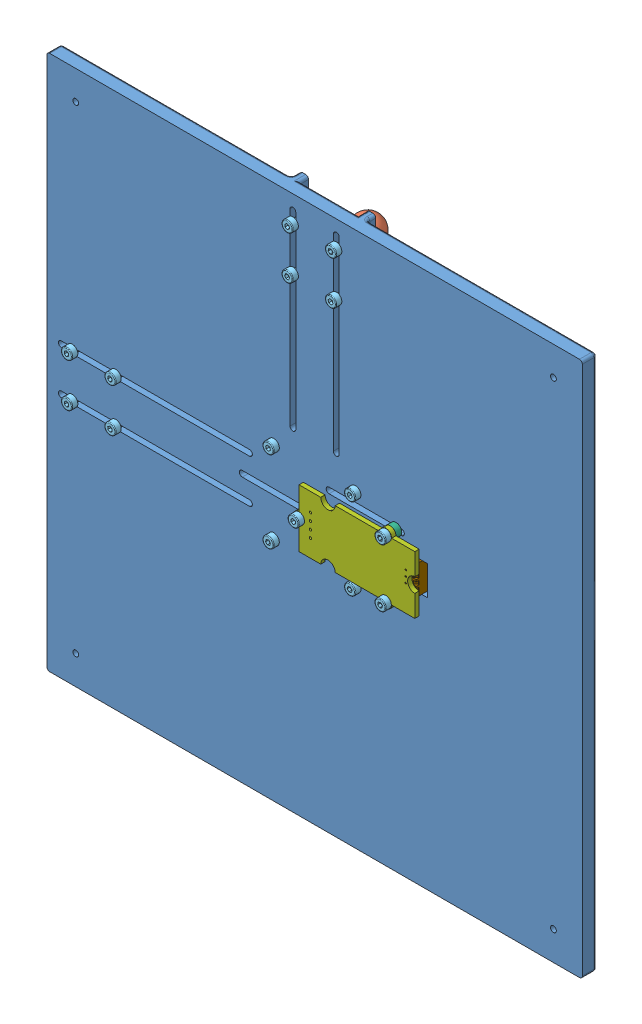
SolidWorks assembly plateau-complet, configuration Défaut. Lengths in mm.
Overall size (185 185 29.5).
45 component instances, 9 part files, 99 mates.
Components (placement in the parent):
- plateau-1: plateau [Défaut] at (22.8083 8.2939 197.5) size (185 185 8)
- support-sphere-ecrou_m2-4: support-sphere-ecrou_m2 [Défaut] at (-53.3917 8.2939 184.1699) x (0 -1 0) z (1 0 0) size (20 18.33 20)
- support-sphere-ecrou_m2-3: support-sphere-ecrou_m2 [Défaut] at (22.8083 84.4939 184.1699) x (1 0 0) z (0 1 0) size (20 18.33 20)
- support-fourchette-ecrou_m2-large-1: support-fourchette-ecrou_m2-large [Défaut] at (22.8083 8.2939 183.5) x (1 0 0) z (0 1 0) size (35 19 35)
- ecrou-h-6: ecrou-h [6007 HU M2] at (30.3083 91.9939 195.1) x (0.866025 -0.5 0) z (-0.5 -0.866025 0) size (4 1.6 4.62)
- ecrou-h-7: ecrou-h [6007 HU M2] at (15.3083 76.9939 195.1) x (-0.866025 -0.5 0) z (-0.5 0.866025 0) size (4 1.6 4.62)
- ecrou-h-8: ecrou-h [6007 HU M2] at (30.3083 76.9939 195.1) x (0.866025 0.5 0) z (0.5 -0.866025 0) size (4 1.6 4.62)
- ecrou-h-9: ecrou-h [6007 HU M2] at (15.3083 91.9939 195.1) x (0 -1 0) z (-1 0 0) size (4 1.6 4.62)
- ecrou-h-10: ecrou-h [6007 HU M2] at (-60.8917 15.7939 195.1) x (-0.5 -0.866025 0) z (-0.866025 0.5 0) size (4 1.6 4.62)
- ecrou-h-11: ecrou-h [6007 HU M2] at (-60.8917 0.7939 195.1) x (0.5 0.866025 0) z (0.866025 -0.5 0) size (4 1.6 4.62)
- ecrou-h-12: ecrou-h [6007 HU M2] at (-45.8917 0.7939 195.1) x (0.5 -0.866025 0) z (-0.866025 -0.5 0) size (4 1.6 4.62)
- ecrou-h-13: ecrou-h [6007 HU M2] at (-45.8917 15.7939 195.1) x (-0.5 -0.866025 0) z (-0.866025 0.5 0) size (4 1.6 4.62)
- vis-chc-15: vis-chc [Vis CHC M2x12] at (-45.8917 0.7939 202.5) x (0.832658 0.553787 0) z (0.553787 -0.832658 0) size (3.8 14 3.8)
- vis-chc-16: vis-chc [Vis CHC M2x12] at (-45.8917 15.7939 202.5) x (0.872712 0.488236 0) z (0.488236 -0.872712 0) size (3.8 14 3.8)
- vis-chc-17: vis-chc [Vis CHC M2x12] at (-60.8917 0.7939 202.5) x (0.878735 -0.477309 0) z (-0.477309 -0.878735 0) size (3.8 14 3.8)
- vis-chc-18: vis-chc [Vis CHC M2x12] at (-60.8917 15.7939 202.5) x (-0.020688 -0.999786 0) z (-0.999786 0.020688 0) size (3.8 14 3.8)
- vis-chc-19: vis-chc [Vis CHC M2x12] at (15.3083 76.9939 202.5) x (-0.459945 -0.887947 0) z (-0.887947 0.459945 0) size (3.8 14 3.8)
- vis-chc-20: vis-chc [Vis CHC M2x12] at (30.3083 76.9939 202.5) x (-0.307246 0.95163 0) z (0.95163 0.307246 0) size (3.8 14 3.8)
- vis-chc-21: vis-chc [Vis CHC M2x12] at (15.3083 91.9939 202.5) x (0.103271 -0.994653 0) z (-0.994653 -0.103271 0) size (3.8 14 3.8)
- vis-chc-22: vis-chc [Vis CHC M2x12] at (30.3083 91.9939 202.5) x (0.948564 0.316586 0) z (0.316586 -0.948564 0) size (3.8 14 3.8)
- vis-chc-23: vis-chc [Vis CHC M2x12] at (8.7083 22.3939 202.5) x (0.719096 0.694911 0) z (0.694911 -0.719096 0) size (3.8 14 3.8)
- vis-chc-24: vis-chc [Vis CHC M2x12] at (36.9083 22.3939 202.5) x (0.587191 0.809448 0) z (0.809448 -0.587191 0) size (3.8 14 3.8)
- vis-chc-25: vis-chc [Vis CHC M2x12] at (8.7083 -5.8061 202.5) x (0.239044 0.971009 0) z (0.971009 -0.239044 0) size (3.8 14 3.8)
- vis-chc-26: vis-chc [Vis CHC M2x12] at (36.9083 -5.8061 202.5) x (0.971464 0.237189 0) z (0.237189 -0.971464 0) size (3.8 14 3.8)
- ecrou-h-14: ecrou-h [6007 HU M2] at (8.7083 22.3939 195.16) x (0.866025 -0.5 0) z (-0.5 -0.866025 0) size (4 1.6 4.62)
- ecrou-h-15: ecrou-h [6007 HU M2] at (8.7083 -5.8061 195.16) x (0 -1 0) z (-1 0 0) size (4 1.6 4.62)
- ecrou-h-16: ecrou-h [6007 HU M2] at (36.9083 -5.8061 195.16) x (0.866025 -0.5 0) z (-0.5 -0.866025 0) size (4 1.6 4.62)
- ecrou-h-17: ecrou-h [6007 HU M2] at (36.9083 22.3939 195.16) x (0.866025 -0.5 0) z (-0.5 -0.866025 0) size (4 1.6 4.62)
- ecrou-h-18: ecrou-h [6007 HU M2] at (-59.6917 90.7939 200.5) x (0.866025 0.5 0) z (0.5 -0.866025 0) size (4 1.6 4.62)
- ecrou-h-19: ecrou-h [6007 HU M2] at (105.3083 90.7939 198.9) x (0.866025 0.5 0) z (-0.5 0.866025 0) size (4 1.6 4.62)
- ecrou-h-20: ecrou-h [6007 HU M2] at (-59.6917 -74.2061 200.5) x (0 -1 0) z (-1 0 0) size (4 1.6 4.62)
- ecrou-h-21: ecrou-h [6007 HU M2] at (105.3083 -74.2061 200.5) x (0 1 0) z (1 0 0) size (4 1.6 4.62)
- vis-chc-30: vis-chc [Vis CHC M2x8] at (50.9161 18.2939 206) x (-0.221467 -0.975168 0) z (-0.975168 0.221467 0) size (3.8 10 3.8)
- vis-chc-32: vis-chc [Vis CHC M2x8] at (50.9161 -1.7061 206) x (-0.923728 -0.383049 0) z (-0.383049 0.923728 0) size (3.8 10 3.8)
- vis-chc-33: vis-chc [Vis CHC M2x8] at (20.9161 8.2939 206) x (-0.787107 -0.616816 0) z (-0.616816 0.787107 0) size (3.8 10 3.8)
- ecrou-h-24: ecrou-h [6007 HU M2] at (20.9161 8.2939 197.9) x (0 -1 0) z (1 0 0) size (4 1.6 4.62)
- ecrou-h-25: ecrou-h [6007 HU M2] at (50.9161 -1.7061 197.9) x (0.866025 0.5 0) z (-0.5 0.866025 0) size (4 1.6 4.62)
- ecrou-h-26: ecrou-h [6007 HU M2] at (50.9161 18.2939 197.9) x (-0.866025 0.5 0) z (-0.5 -0.866025 0) size (4 1.6 4.62)
- entretoise-grove-1: entretoise-grove [Défaut] at (50.9161 18.2939 202.5) x (0.992185 0.124776 0) z (0 0 1) size (4 4 2)
- entretoise-grove-2: entretoise-grove [Défaut] at (20.9161 8.2939 202.5) x (0.16979 0.98548 0) z (0 0 1) size (4 4 2)
- entretoise-grove-3: entretoise-grove [Défaut] at (50.9161 -1.7061 202.5) x (0.064788 0.997899 0) z (0 0 1) size (4 4 2)
- Grove IMU - droit-1: Grove IMU - droit [Défaut] at (42.9373 5.8987 163.25) x (0 -1 0) z (0 0 1) size (24 42 9.5)
  - Grove IMU Board-1: Grove IMU Board [Défaut] at (-2.3952 -22.0212 41.25) size (24 42 1.5)
  - MPU9150-1: MPU9150 [Défaut] at (-3.0078 -7.8003 40.45) size (4 4 0.8)
  - Connecteur Grove - droit-1: Connecteur Grove - droit [Défaut] at (-2.3952 11.9788 41.25) x (-1 0 0) z (0 -1 0) size (10 11 5)
Mates (geometry in assembly coordinates):
- Coïncidente5: coincident anti-aligned: plane of plateau-1 through (22.8083 8.2939 197.5) normal (0 0 -1); plane of support-sphere-ecrou_m2-4 through (-53.3917 8.2939 197.5) normal (0 0 1)
- Coïncidente8: coincident anti-aligned: plane of plateau-1 through (22.8083 8.2939 197.5) normal (0 0 -1); plane of support-sphere-ecrou_m2-3 through (22.8083 84.4939 197.5) normal (0 0 1)
- Coïncidente12: coincident anti-aligned: plane of plateau-1 through (22.8083 8.2939 197.5) normal (0 0 -1); plane of support-fourchette-ecrou_m2-large-1 through (22.8083 8.2939 197.5) normal (0 0 1)
- Coaxiale9: concentric anti-aligned: cylinder of support-sphere-ecrou_m2-3 through (30.3083 91.9939 197.501) axis (0 0 -1) radius 1; cylinder of ecrou-h-m2-6 through (30.3083 91.9939 193.5) axis (0 0 1) radius 0.7835
- Coïncidente26: coincident anti-aligned: plane of support-sphere-ecrou_m2-3 through (22.8083 84.4939 195.1) normal (0 0 -1); plane of ecrou-h-m2-6 through (32.6177 91.9939 195.1) normal (0 0 1)
- Parallèle1: parallel anti-aligned: plane of support-sphere-ecrou_m2-3 through (27.9783 91.9939 195.1) normal (0.866025 -0.5 0); plane of ecrou-h-m2-6 through (29.1536 93.9939 193.5) normal (-0.866025 0.5 0)
- Coaxiale10: concentric anti-aligned: cylinder of support-sphere-ecrou_m2-3 through (15.3083 91.9939 197.501) axis (0 0 -1) radius 1; cylinder of ecrou-h-m2-9 through (15.3083 91.9939 193.5) axis (0 0 1) radius 0.7835
- Parallèle2: parallel anti-aligned: plane of support-sphere-ecrou_m2-3 through (14.1433 94.0118 195.1) normal (0 -1 0); plane of ecrou-h-m2-9 through (16.463 93.9939 193.5) normal (0 1 0)
- Coïncidente29: coincident anti-aligned: plane of support-sphere-ecrou_m2-3 through (22.8083 84.4939 195.1) normal (0 0 -1); plane of ecrou-h-m2-9 through (16.463 89.9939 195.1) normal (0 0 1)
- Coaxiale11: concentric anti-aligned: cylinder of support-sphere-ecrou_m2-3 through (15.3083 76.9939 197.501) axis (0 0 -1) radius 1; cylinder of ecrou-h-m2-7 through (15.3083 76.9939 193.5) axis (0 0 1) radius 0.7835
- Parallèle3: parallel anti-aligned: plane of support-sphere-ecrou_m2-3 through (12.9783 76.9939 195.1) normal (0.866025 -0.5 0); plane of ecrou-h-m2-7 through (14.1536 78.9939 193.5) normal (-0.866025 0.5 0)
- Coïncidente31: coincident anti-aligned: plane of support-sphere-ecrou_m2-3 through (22.8083 84.4939 195.1) normal (0 0 -1); plane of ecrou-h-m2-7 through (14.1536 74.9939 195.1) normal (0 0 1)
- Coaxiale12: concentric anti-aligned: cylinder of support-sphere-ecrou_m2-3 through (30.3083 76.9939 197.501) axis (0 0 -1) radius 1; cylinder of ecrou-h-m2-8 through (30.3083 76.9939 193.5) axis (0 0 1) radius 0.7835
- Parallèle4: parallel anti-aligned: plane of support-sphere-ecrou_m2-3 through (32.6383 76.9939 195.1) normal (-0.866025 0.5 0); plane of ecrou-h-m2-8 through (31.463 74.9939 193.5) normal (0.866025 -0.5 0)
- Coïncidente32: coincident anti-aligned: plane of support-sphere-ecrou_m2-3 through (22.8083 84.4939 195.1) normal (0 0 -1); plane of ecrou-h-m2-8 through (31.463 78.9939 195.1) normal (0 0 1)
- Coaxiale13: concentric anti-aligned: cylinder of support-sphere-ecrou_m2-4 through (-60.8917 15.7939 197.501) axis (0 0 -1) radius 1; cylinder of ecrou-h-m2-10 through (-60.8917 15.7939 193.5) axis (0 0 1) radius 0.7835
- Coaxiale14: concentric anti-aligned: cylinder of support-sphere-ecrou_m2-4 through (-60.8917 0.7939 197.501) axis (0 0 -1) radius 1; cylinder of ecrou-h-m2-11 through (-60.8917 0.7939 193.5) axis (0 0 1) radius 0.7835
- Coaxiale15: concentric anti-aligned: cylinder of support-sphere-ecrou_m2-4 through (-45.8917 0.7939 197.501) axis (0 0 -1) radius 1; cylinder of ecrou-h-m2-12 through (-45.8917 0.7939 193.5) axis (0 0 1) radius 0.7835
- Coaxiale16: concentric anti-aligned: cylinder of support-sphere-ecrou_m2-4 through (-45.8917 15.7939 197.501) axis (0 0 -1) radius 1; cylinder of ecrou-h-m2-13 through (-45.8917 15.7939 193.5) axis (0 0 1) radius 0.7835
- Parallèle5: parallel anti-aligned: plane of support-sphere-ecrou_m2-4 through (-43.8738 16.9589 195.1) normal (-1 0 0); plane of ecrou-h-m2-13 through (-43.8917 14.6392 193.5) normal (1 0 0)
- Parallèle6: parallel anti-aligned: plane of support-sphere-ecrou_m2-4 through (-58.8738 16.9589 195.1) normal (-1 0 0); plane of ecrou-h-m2-10 through (-58.8917 14.6392 193.5) normal (1 0 0)
- Parallèle7: parallel anti-aligned: plane of support-sphere-ecrou_m2-4 through (-58.8738 -0.3711 195.1) normal (-0.5 0.866025 0); plane of ecrou-h-m2-11 through (-60.8917 -1.5155 193.5) normal (0.5 -0.866025 0)
- Parallèle8: parallel anti-aligned: plane of support-sphere-ecrou_m2-4 through (-43.8738 -0.3711 195.1) normal (-0.5 0.866025 0); plane of ecrou-h-m2-12 through (-45.8917 -1.5155 193.5) normal (0.5 -0.866025 0)
- Coïncidente37: coincident anti-aligned: plane of support-sphere-ecrou_m2-4 through (-53.3917 8.2939 195.1) normal (0 0 -1); plane of ecrou-h-m2-10 through (-60.8917 13.4845 195.1) normal (0 0 1)
- Coïncidente38: coincident anti-aligned: plane of support-sphere-ecrou_m2-4 through (-53.3917 8.2939 195.1) normal (0 0 -1); plane of ecrou-h-m2-13 through (-45.8917 13.4845 195.1) normal (0 0 1)
- Coïncidente39: coincident anti-aligned: plane of support-sphere-ecrou_m2-4 through (-53.3917 8.2939 195.1) normal (0 0 -1); plane of ecrou-h-m2-11 through (-60.8917 3.1033 195.1) normal (0 0 1)
- Coïncidente40: coincident anti-aligned: plane of support-sphere-ecrou_m2-4 through (-53.3917 8.2939 195.1) normal (0 0 -1); plane of ecrou-h-m2-12 through (-43.8917 -0.3608 195.1) normal (0 0 1)
- Coaxiale17: concentric anti-aligned: cylinder of support-sphere-ecrou_m2-3 through (30.3083 91.9939 197.501) axis (0 0 -1) radius 1; cylinder of vis-chc-m2x10-8 through (30.3083 91.9939 190.5) axis (0 0 1) radius 1
- Coaxiale18: concentric anti-aligned: cylinder of support-sphere-ecrou_m2-3 through (15.3083 91.9939 197.501) axis (0 0 -1) radius 1; cylinder of vis-chc-m2x10-9 through (15.3083 91.9939 190.5) axis (0 0 1) radius 1
- Coaxiale19: concentric anti-aligned: cylinder of support-sphere-ecrou_m2-3 through (30.3083 76.9939 197.501) axis (0 0 -1) radius 1; cylinder of vis-chc-m2x10-11 through (30.3083 76.9939 190.5) axis (0 0 1) radius 1
- Coaxiale20: concentric anti-aligned: cylinder of support-sphere-ecrou_m2-3 through (15.3083 76.9939 197.501) axis (0 0 -1) radius 1; cylinder of vis-chc-m2x10-10 through (15.3083 76.9939 190.5) axis (0 0 1) radius 1
- Coaxiale21: concentric anti-aligned: cylinder of support-sphere-ecrou_m2-4 through (-45.8917 0.7939 197.501) axis (0 0 -1) radius 1; cylinder of vis-chc-m2-15 through (-45.8917 0.7939 190.5) axis (0 0 1) radius 1
- Coaxiale22: concentric anti-aligned: cylinder of support-sphere-ecrou_m2-4 through (-60.8917 0.7939 197.501) axis (0 0 -1) radius 1; cylinder of vis-chc-m2-17 through (-60.8917 0.7939 190.5) axis (0 0 1) radius 1
- Coaxiale23: concentric anti-aligned: cylinder of support-sphere-ecrou_m2-4 through (-60.8917 15.7939 197.501) axis (0 0 -1) radius 1; cylinder of vis-chc-m2-18 through (-60.8917 15.7939 190.5) axis (0 0 1) radius 1
- Coaxiale24: concentric anti-aligned: cylinder of support-sphere-ecrou_m2-4 through (-45.8917 15.7939 197.501) axis (0 0 -1) radius 1; cylinder of vis-chc-m2-16 through (-45.8917 15.7939 190.5) axis (0 0 1) radius 1
- Coïncidente41: coincident anti-aligned: plane of plateau-1 through (22.8083 8.2939 202.5) normal (0 0 1); plane of vis-chc-m2x10-10 through (15.3083 76.9939 202.5) normal (0 0 -1)
- Coïncidente42: coincident anti-aligned: plane of plateau-1 through (22.8083 8.2939 202.5) normal (0 0 1); plane of vis-chc-m2x10-9 through (15.3083 91.9939 202.5) normal (0 0 -1)
- Coïncidente43: coincident anti-aligned: plane of plateau-1 through (22.8083 8.2939 202.5) normal (0 0 1); plane of vis-chc-m2x10-8 through (30.3083 91.9939 202.5) normal (0 0 -1)
- Coïncidente44: coincident anti-aligned: plane of plateau-1 through (22.8083 8.2939 202.5) normal (0 0 1); plane of vis-chc-m2x10-11 through (30.3083 76.9939 202.5) normal (0 0 -1)
- Coïncidente45: coincident anti-aligned: plane of plateau-1 through (22.8083 8.2939 202.5) normal (0 0 1); plane of vis-chc-m2-17 through (-60.8917 0.7939 202.5) normal (0 0 -1)
- Coïncidente46: coincident anti-aligned: plane of plateau-1 through (22.8083 8.2939 202.5) normal (0 0 1); plane of vis-chc-m2-15 through (-45.8917 0.7939 202.5) normal (0 0 -1)
- Coïncidente47: coincident anti-aligned: plane of plateau-1 through (22.8083 8.2939 202.5) normal (0 0 1); plane of vis-chc-m2-16 through (-45.8917 15.7939 202.5) normal (0 0 -1)
- Coïncidente48: coincident anti-aligned: plane of plateau-1 through (22.8083 8.2939 202.5) normal (0 0 1); plane of vis-chc-m2-18 through (-60.8917 15.7939 202.5) normal (0 0 -1)
- Distance6: distance = 13.8 mm: cylinder of support-sphere-ecrou_m2-4 through (-53.3917 8.2939 193.5) axis (0 0 1) radius 2.5; plane of plateau-1 through (-69.6917 100.7939 202.5) normal (-1 0 0)
- Distance7: distance = 13.8 mm: cylinder of support-sphere-ecrou_m2-3 through (22.8083 84.4939 193.5) axis (0 0 1) radius 2.5; plane of plateau-1 through (-69.6917 100.7939 202.5) normal (0 1 0)
- Coaxiale25: concentric anti-aligned: cylinder of support-fourchette-ecrou_m2-large-1 through (36.9083 22.3939 197.501) axis (0 0 -1) radius 1; cylinder of ecrou-h-m2-17 through (36.9083 22.3939 193.56) axis (0 0 1) radius 0.7835
- Parallèle9: parallel anti-aligned: plane of support-fourchette-ecrou_m2-large-1 through (35.7433 24.4118 195.16) normal (0 -1 0); plane of ecrou-h-m2-17 through (38.063 24.3939 193.56) normal (0 1 0)
- Coïncidente50: coincident anti-aligned: plane of support-fourchette-ecrou_m2-large-1 through (22.8083 8.2939 195.16) normal (0 0 -1); plane of ecrou-h-m2-17 through (39.2177 22.3939 195.16) normal (0 0 1)
- Coaxiale26: concentric anti-aligned: cylinder of support-fourchette-ecrou_m2-large-1 through (36.9083 -5.8061 197.501) axis (0 0 -1) radius 1; cylinder of ecrou-h-m2-16 through (36.9083 -5.8061 193.56) axis (0 0 1) radius 0.7835
- Coïncidente51: coincident anti-aligned: plane of support-fourchette-ecrou_m2-large-1 through (22.8083 8.2939 195.16) normal (0 0 -1); plane of ecrou-h-m2-16 through (39.2177 -5.8061 195.16) normal (0 0 1)
- Parallèle10: parallel anti-aligned: plane of support-fourchette-ecrou_m2-large-1 through (35.7433 -3.7882 195.16) normal (0 -1 0); plane of ecrou-h-m2-16 through (38.063 -3.8061 193.56) normal (0 1 0)
- Coaxiale27: concentric anti-aligned: cylinder of support-fourchette-ecrou_m2-large-1 through (8.7083 -5.8061 197.501) axis (0 0 -1) radius 1; cylinder of ecrou-h-m2-15 through (8.7083 -5.8061 193.56) axis (0 0 1) radius 0.7835
- Parallèle11: parallel anti-aligned: plane of support-fourchette-ecrou_m2-large-1 through (9.8733 -7.8239 195.16) normal (0 1 0); plane of ecrou-h-m2-15 through (7.5536 -7.8061 193.56) normal (0 -1 0)
- Coïncidente54: coincident anti-aligned: plane of support-fourchette-ecrou_m2-large-1 through (22.8083 8.2939 195.16) normal (0 0 -1); plane of ecrou-h-m2-15 through (9.863 -7.8061 195.16) normal (0 0 1)
- Coaxiale28: concentric anti-aligned: cylinder of support-fourchette-ecrou_m2-large-1 through (8.7083 22.3939 197.501) axis (0 0 -1) radius 1; cylinder of ecrou-h-m2-14 through (8.7083 22.3939 193.56) axis (0 0 1) radius 0.7835
- Parallèle12: parallel anti-aligned: plane of support-fourchette-ecrou_m2-large-1 through (7.5433 24.4118 195.16) normal (0 -1 0); plane of ecrou-h-m2-14 through (9.863 24.3939 193.56) normal (0 1 0)
- Coïncidente56: coincident anti-aligned: plane of support-fourchette-ecrou_m2-large-1 through (22.8083 8.2939 195.16) normal (0 0 -1); plane of ecrou-h-m2-14 through (11.0177 22.3939 195.16) normal (0 0 1)
- Coaxiale29: concentric anti-aligned: cylinder of plateau-1 through (8.7083 -5.8061 202.501) axis (0 0 -1) radius 1; cylinder of vis-chc-m2-25 through (8.7083 -5.8061 190.5) axis (0 0 1) radius 1
- Coïncidente57: coincident anti-aligned: plane of plateau-1 through (22.8083 8.2939 202.5) normal (0 0 1); plane of vis-chc-m2-25 through (8.7083 -5.8061 202.5) normal (0 0 -1)
- Coaxiale30: concentric anti-aligned: cylinder of plateau-1 through (36.9083 -5.8061 202.501) axis (0 0 -1) radius 1; cylinder of vis-chc-26 through (36.9083 -5.8061 190.5) axis (0 0 1) radius 1
- Coïncidente58: coincident anti-aligned: plane of plateau-1 through (22.8083 8.2939 202.5) normal (0 0 1); plane of vis-chc-26 through (36.9083 -5.8061 202.5) normal (0 0 -1)
- Coaxiale31: concentric anti-aligned: cylinder of plateau-1 through (8.7083 22.3939 202.501) axis (0 0 -1) radius 1; cylinder of vis-chc-m2-23 through (8.7083 22.3939 190.5) axis (0 0 1) radius 1
- Coïncidente59: coincident anti-aligned: plane of plateau-1 through (22.8083 8.2939 202.5) normal (0 0 1); plane of vis-chc-m2-23 through (8.7083 22.3939 202.5) normal (0 0 -1)
- Coaxiale32: concentric anti-aligned: cylinder of plateau-1 through (36.9083 22.3939 202.501) axis (0 0 -1) radius 1; cylinder of vis-chc-m2-24 through (36.9083 22.3939 190.5) axis (0 0 1) radius 1
- Coïncidente60: coincident anti-aligned: plane of plateau-1 through (22.8083 8.2939 202.5) normal (0 0 1); plane of vis-chc-m2-24 through (36.9083 22.3939 202.5) normal (0 0 -1)
- Coaxiale33: concentric anti-aligned: circle of plateau-1; circle of ecrou-h-m2-19
- Coaxiale34: concentric anti-aligned: cylinder of plateau-1 through (-59.6917 90.7939 202.501) axis (0 0 -1) radius 1; cylinder of ecrou-h-18 through (-59.6917 90.7939 198.9) axis (0 0 1) radius 0.7835
- Coaxiale35: concentric anti-aligned: cylinder of plateau-1 through (-59.6917 -74.2061 202.501) axis (0 0 -1) radius 1; cylinder of ecrou-h-20 through (-59.6917 -74.2061 198.9) axis (0 0 1) radius 0.7835
- Coaxiale36: concentric anti-aligned: cylinder of plateau-1 through (105.3083 -74.2061 202.501) axis (0 0 -1) radius 1; cylinder of ecrou-h-21 through (105.3083 -74.2061 198.9) axis (0 0 1) radius 0.7835
- Coaxiale37: concentric aligned: cylinder of ecrou-h-m2-16 through (36.9083 -5.8061 193.56) axis (0 0 1) radius 0.7835; cylinder of vis-chc-26 through (36.9083 -5.8061 190.5) axis (0 0 1) radius 1
- Coaxiale38: concentric aligned: cylinder of ecrou-h-m2-14 through (8.7083 22.3939 193.56) axis (0 0 1) radius 0.7835; cylinder of vis-chc-m2-23 through (8.7083 22.3939 190.5) axis (0 0 1) radius 1
- Parallèle13: parallel aligned: plane of plateau-1 through (-69.6917 100.7939 202.5) normal (0 1 0); plane of support-sphere-ecrou_m2-3 through (12.8083 94.4939 197.5) normal (0 1 0)
- Distance8: distance = 0.1 mm anti-aligned: plane of support-sphere-ecrou_m2-3 through (12.8083 94.4939 197.5) normal (-1 0 0); plane of plateau-1 through (12.7083 30.7939 194.5) normal (1 0 0)
- Parallèle14: parallel aligned: plane of plateau-1 through (-69.6917 100.7939 202.5) normal (-1 0 0); plane of support-sphere-ecrou_m2-4 through (-63.3917 18.2939 197.5) normal (-1 0 0)
- Distance9: distance = 0.1 mm anti-aligned: plane of support-sphere-ecrou_m2-4 through (-43.3917 18.2939 197.5) normal (0 1 0); plane of plateau-1 through (0.3083 18.3939 194.5) normal (0 -1 0)
- Parallèle15: parallel aligned: plane of plateau-1 through (115.3083 100.7939 202.5) normal (1 0 0); plane of Grove IMU - droit-1/Grove IMU Board-1 through (60.9161 -1.7061 206) normal (1 0 0)
- Tangent1: tangent anti-aligned: plane of plateau-1 through (27.8083 -2.7061 194.499) normal (0 1 0); cylinder of Grove IMU - droit-1/Grove IMU Board-1 through (50.9161 -1.7061 204.5) axis (0 0 1) radius 1
- Distance10: distance = 2 mm anti-aligned: plane of Grove IMU - droit-1/Grove IMU Board-1 through (30.9161 18.2939 204.5) normal (0 0 -1); plane of plateau-1 through (22.8083 8.2939 202.5) normal (0 0 1)
- Coaxiale45: concentric aligned: cylinder of Grove IMU - droit-1/Grove IMU Board-1 through (50.9161 18.2939 204.5) axis (0 0 1) radius 1; cylinder of vis-chc-30 through (50.9161 18.2939 198) axis (0 0 1) radius 1
- Coïncidente70: coincident anti-aligned: plane of Grove IMU - droit-1/Grove IMU Board-1 through (30.9161 18.2939 206) normal (0 0 1); plane of vis-chc-30 through (50.9161 18.2939 206) normal (0 0 -1)
- Coaxiale46: concentric anti-aligned: cylinder of vis-chc-30 through (50.9161 18.2939 198) axis (0 0 1) radius 1; cylinder of ecrou-h-26 through (50.9161 18.2939 199.5) axis (0 0 -1) radius 0.7835
- Parallèle18: parallel anti-aligned: plane of plateau-1 through (55.8083 20.3939 199.5) normal (0 -1 0); plane of ecrou-h-26 through (49.7614 20.2939 199.5) normal (0 1 0)
- Coïncidente72: coincident anti-aligned: plane of plateau-1 through (22.8083 8.2939 199.5) normal (0 0 -1); plane of ecrou-h-26 through (49.7614 20.2939 199.5) normal (0 0 1)
- Coaxiale47: concentric aligned: cylinder of Grove IMU - droit-1/Grove IMU Board-1 through (50.9161 -1.7061 204.5) axis (0 0 1) radius 1; cylinder of vis-chc-32 through (50.9161 -1.7061 198) axis (0 0 1) radius 1
- Coaxiale48: concentric aligned: cylinder of Grove IMU - droit-1/Grove IMU Board-1 through (20.9161 8.2939 204.5) axis (0 0 1) radius 1; cylinder of vis-chc-33 through (20.9161 8.2939 198) axis (0 0 1) radius 1
- Coïncidente73: coincident anti-aligned: plane of Grove IMU - droit-1/Grove IMU Board-1 through (30.9161 18.2939 206) normal (0 0 1); plane of vis-chc-32 through (50.9161 -1.7061 206) normal (0 0 -1)
- Coïncidente74: coincident anti-aligned: plane of Grove IMU - droit-1/Grove IMU Board-1 through (30.9161 18.2939 206) normal (0 0 1); plane of vis-chc-33 through (20.9161 8.2939 206) normal (0 0 -1)
- Coaxiale50: concentric anti-aligned: cylinder of vis-chc-32 through (50.9161 -1.7061 198) axis (0 0 1) radius 1; cylinder of ecrou-h-25 through (50.9161 -1.7061 199.5) axis (0 0 -1) radius 0.7835
- Parallèle19: parallel anti-aligned: plane of plateau-1 through (55.8083 0.3939 199.5) normal (0 -1 0); plane of ecrou-h-25 through (49.7614 0.2939 199.5) normal (0 1 0)
- Coïncidente76: coincident anti-aligned: plane of plateau-1 through (22.8083 8.2939 199.5) normal (0 0 -1); plane of ecrou-h-25 through (53.2255 -1.7061 199.5) normal (0 0 1)
- Coaxiale51: concentric anti-aligned: cylinder of vis-chc-33 through (20.9161 8.2939 198) axis (0 0 1) radius 1; cylinder of ecrou-h-24 through (20.9161 8.2939 199.5) axis (0 0 -1) radius 0.7835
- Parallèle20: parallel anti-aligned: plane of plateau-1 through (25.8083 10.3939 199.5) normal (0 -1 0); plane of ecrou-h-24 through (19.7614 10.2939 199.5) normal (0 1 0)
- Coïncidente78: coincident anti-aligned: plane of plateau-1 through (22.8083 8.2939 199.5) normal (0 0 -1); plane of ecrou-h-24 through (19.7614 6.2939 199.5) normal (0 0 1)
- Coaxiale52: concentric anti-aligned: cylinder of vis-chc-32 through (50.9161 -1.7061 198) axis (0 0 1) radius 1; cylinder of entretoise-grove-3 through (50.9161 -1.7061 204.5) axis (0 0 -1) radius 1
- Coïncidente79: coincident anti-aligned: plane of plateau-1 through (22.8083 8.2939 202.5) normal (0 0 1); plane of entretoise-grove-3 through (50.9161 -1.7061 202.5) normal (0 0 -1)
- Coaxiale53: concentric anti-aligned: cylinder of vis-chc-30 through (50.9161 18.2939 198) axis (0 0 1) radius 1; cylinder of entretoise-grove-1 through (50.9161 18.2939 204.5) axis (0 0 -1) radius 1
- Coïncidente80: coincident anti-aligned: plane of plateau-1 through (22.8083 8.2939 202.5) normal (0 0 1); plane of entretoise-grove-1 through (50.9161 18.2939 202.5) normal (0 0 -1)
- Coaxiale54: concentric anti-aligned: cylinder of vis-chc-33 through (20.9161 8.2939 198) axis (0 0 1) radius 1; cylinder of entretoise-grove-2 through (20.9161 8.2939 204.5) axis (0 0 -1) radius 1
- Coïncidente81: coincident anti-aligned: plane of plateau-1 through (22.8083 8.2939 202.5) normal (0 0 1); plane of entretoise-grove-2 through (20.9161 8.2939 202.5) normal (0 0 -1)
